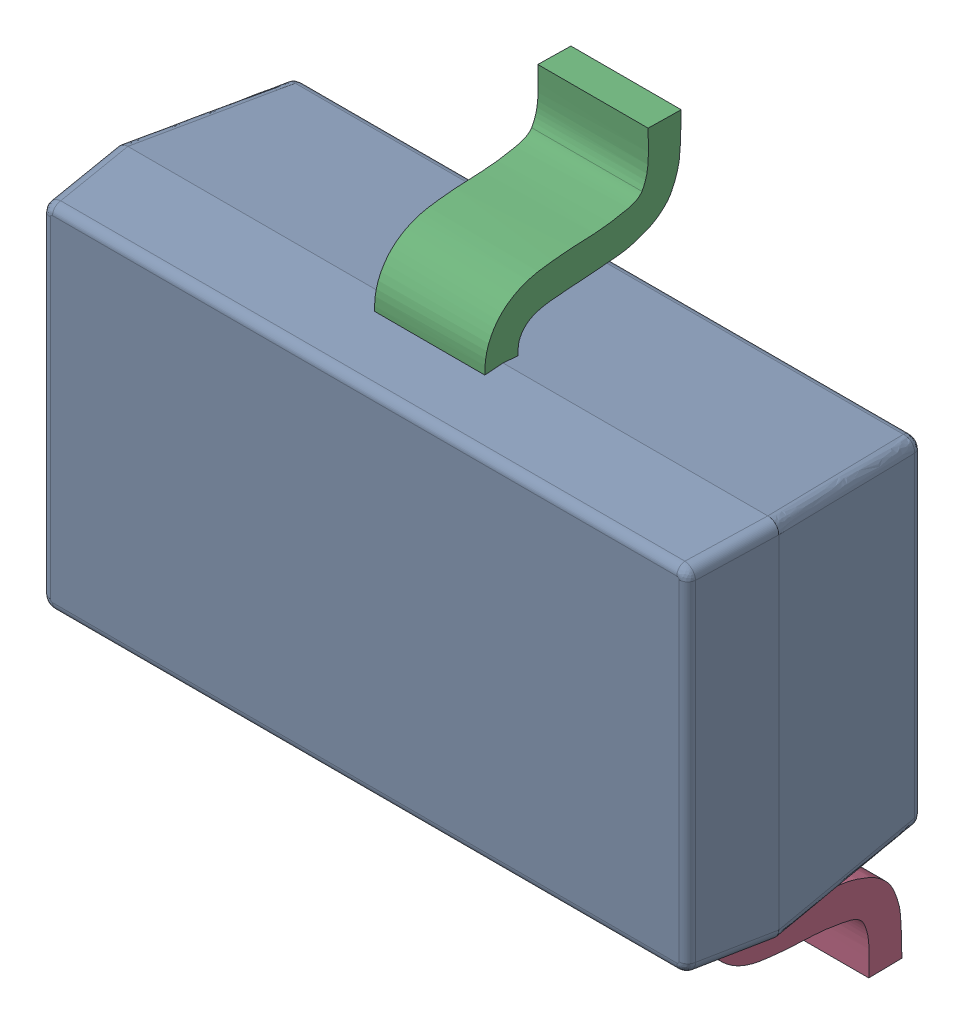
SolidWorks assembly U1_1, configuration Default. Lengths in mm.
Overall size (3.01 2.91 1.23).
3 component instances, 2 part files, 0 mates.
Components (placement in the parent):
- SOT23-3_1-1: SOT23-3_1 [Default] at (13.9939 25.8873 0) x (0 -1 0) z (0 0 1) size (2.91 3.01 1.23)
- 5808185472-1: 5808185472 [Default] at (14.097 26.162 0) size (0.25 0.25 0.25)
  - Extruded_1-1: Extruded_1 [Default] at origin size (0.25 0.25 0.25)
